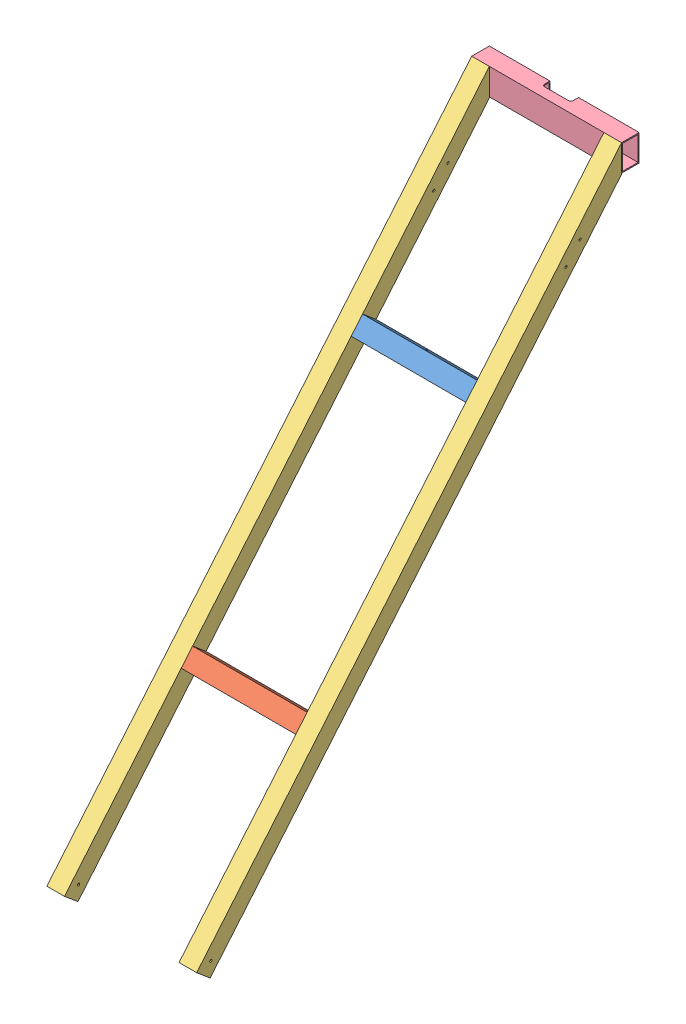
SolidWorks assembly GE-18078, configuration Default. Lengths in mm.
Overall size (431.8 1491.97 1275.31).
5 component instances, 4 part files, 15 mates.
Components (placement in the parent):
- GE-18078-4-1: GE-18078-4 [Default] at (0 2011.5748 -444.9466) x (0 -1 0) z (0 0 1) size (71.57 330.2 71.57)
- GE-18078-3-1: GE-18078-3 [Default] at (0 867.3116 515.2042) x (0 -1 0) z (0 0 1) size (71.57 330.2 71.57)
- GE-18078-2-1: GE-18078-2 [Default] at (381 1451.0375 25.4) x (0 -1 0) z (0 0 1) size (1491.97 50.8 1224.51)
- GE-18078-2-2: GE-18078-2 [Default] at (0 1451.0375 25.4) x (0 -1 0) z (0 0 1) size (1491.97 50.8 1224.51)
- GE-18078-1-1: GE-18078-1 [Default] at (0 1453.8683 25.4) x (0 -1 0) z (0 0 1) size (76.2 431.8 50.8)
Mates (geometry in assembly coordinates):
- Coincident1: coincident aligned: plane of GE-18078-2-1 through (215.9 922.9185 637.6552) normal (1 0 0); plane of GE-18078-1-1 through (215.9 1630.8027 25.4) normal (1 0 0)
- Coincident2: coincident: line of GE-18078-2-1 through (215.9 1668.9027 50.8) axis (-1 0 0); plane of GE-18078-1-1 through (-215.9 1668.9027 25.4) normal (0 1 0)
- Coincident3: coincident anti-aligned: plane of GE-18078-2-1 through (215.9 1653.4828 50.8) normal (0 0 -1); plane of GE-18078-1-1 through (-215.9 1630.8027 50.8) normal (0 0 1)
- Distance2: distance = 523.6589 mm aligned: plane of GE-18078-2-2 through (-165.1 21.5741 1262.1064) normal (0 -0.766044 0.642788); plane of GE-18078-3-1 through (165.1 422.7433 925.5325) normal (0 -0.766044 0.642788)
- Coincident11: coincident aligned: plane of GE-18078-3-1 through (165.1 766.1331 808.3136) normal (0 0.642788 0.766044); plane of GE-18078-2-2 through (-165.1 1349.859 318.5094) normal (0 0.642788 0.766044)
- Distance3: distance = 1285.6589 mm aligned: plane of GE-18078-2-2 through (-165.1 21.5741 1262.1064) normal (0 -0.766044 0.642788); plane of GE-18078-4-1 through (165.1 1006.7018 436.0056) normal (0 -0.766044 0.642788)
- Coincident13: coincident anti-aligned: plane of GE-18078-4-1 through (-165.1 1483.4558 192.7086) normal (-1 0 0); plane of GE-18078-2-2 through (-165.1 922.9185 637.6552) normal (1 0 0)
- Coincident14: coincident aligned: plane of GE-18078-4-1 through (165.1 1910.3963 -151.8372) normal (0 0.642788 0.766044); plane of GE-18078-2-2 through (-165.1 1349.859 318.5094) normal (0 0.642788 0.766044)
- Coincident15: coincident anti-aligned: plane of GE-18078-4-1 through (165.1 1483.4558 192.7086) normal (1 0 0); plane of GE-18078-2-1 through (165.1 922.9185 637.6552) normal (-1 0 0)
- Coincident16: coincident anti-aligned: plane of GE-18078-3-1 through (165.1 339.1927 1152.8594) normal (1 0 0); plane of GE-18078-2-1 through (165.1 922.9185 637.6552) normal (-1 0 0)
- Coincident17: coincident anti-aligned: plane of GE-18078-2-2 through (-165.1 1653.4828 50.8) normal (0 0 -1); plane of GE-18078-1-1 through (-215.9 1630.8027 50.8) normal (0 0 1)
- Coincident18: coincident: line of GE-18078-2-2 through (-165.1 1668.9027 50.8) axis (-1 0 0); plane of GE-18078-1-1 through (-215.9 1668.9027 25.4) normal (0 1 0)
- Coincident19: coincident anti-aligned: plane of GE-18078-1-1 through (-215.9 1453.8683 0) normal (0 0 -1); plane of assembly
- Coincident20: coincident aligned: plane of GE-18078-1-1 through (0 1453.8683 25.4) normal (1 0 0); plane of assembly
- Coincident21: coincident: line of GE-18078-2-1 through (215.9 0 1236.3953) axis (-1 0 0); plane of assembly
